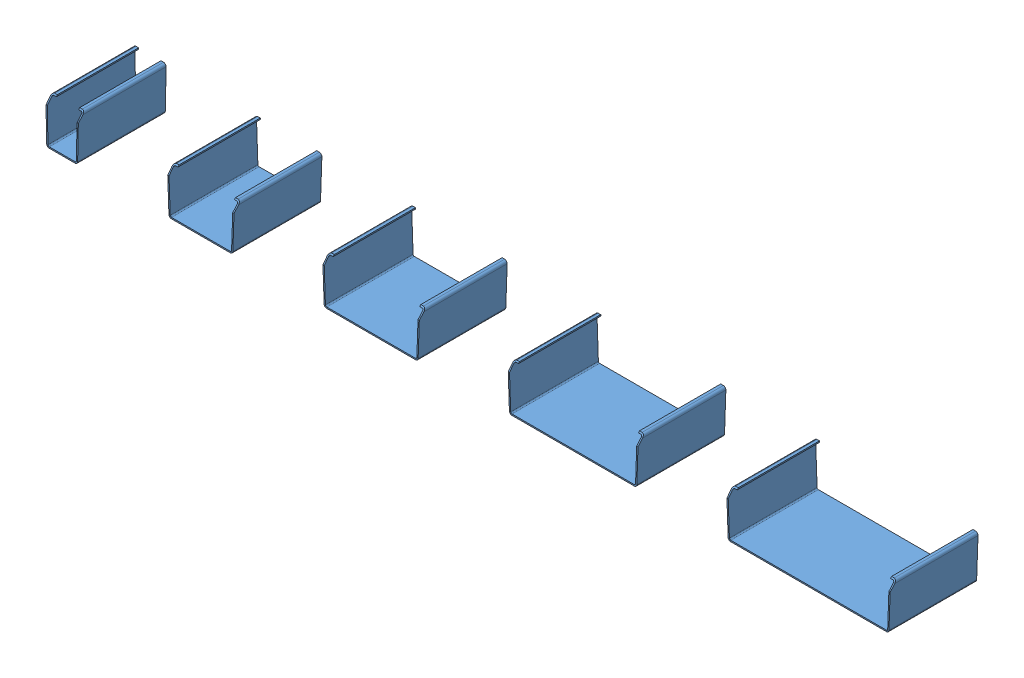
SolidWorks assembly solidworksAssembly2014SP0, configuration Default. Lengths in mm.
Overall size (656.9 34.3 68.2).
5 component instances, 1 part files, 5 mates.
Components (placement in the parent):
- solidworksPart2014SP0-1: solidworksPart2014SP0 [Default] at origin size (127.25 34.3 68.2)
- solidworksPart2014SP0-2: solidworksPart2014SP0 [Config2] at (-183.137 0 0) size (101.24 34.3 68.2)
- solidworksPart2014SP0-3: solidworksPart2014SP0 [Config1] at (-340.2739 0 0) size (75.25 34.3 68.2)
- solidworksPart2014SP0-4: solidworksPart2014SP0 [Config3] at (-472.711 0 0) size (51.85 34.3 68.2)
- solidworksPart2014SP0-5: solidworksPart2014SP0 [Config4] at (-580.62 0 0) size (25.32 34.3 68.2)
Mates (geometry in assembly coordinates):
- Coincident5: coincident aligned: plane of solidworksPart2014SP0-1 through (0 1 34.1) normal (0 1 0); plane of solidworksPart2014SP0-2 through (-183.137 1 34.1) normal (0 1 0)
- Coincident6: coincident aligned: plane of solidworksPart2014SP0-1 through (-60.5686 2 34.1) normal (0 0 1); plane of solidworksPart2014SP0-2 through (-230.7054 2 34.1) normal (0 0 1)
- Coincident8: coincident aligned: plane of solidworksPart2014SP0-2 through (-183.137 1 34.1) normal (0 1 0); plane of solidworksPart2014SP0-3 through (-340.2739 1 34.1) normal (0 1 0)
- Coincident12: coincident aligned: plane of solidworksPart2014SP0-3 through (-340.2739 1 34.1) normal (0 1 0); plane of solidworksPart2014SP0-4 through (-472.711 1 34.1) normal (0 1 0)
- Coincident15: coincident aligned: plane of solidworksPart2014SP0-4 through (-472.711 1 34.1) normal (0 1 0); plane of solidworksPart2014SP0-5 through (-580.62 1 34.1) normal (0 1 0)
